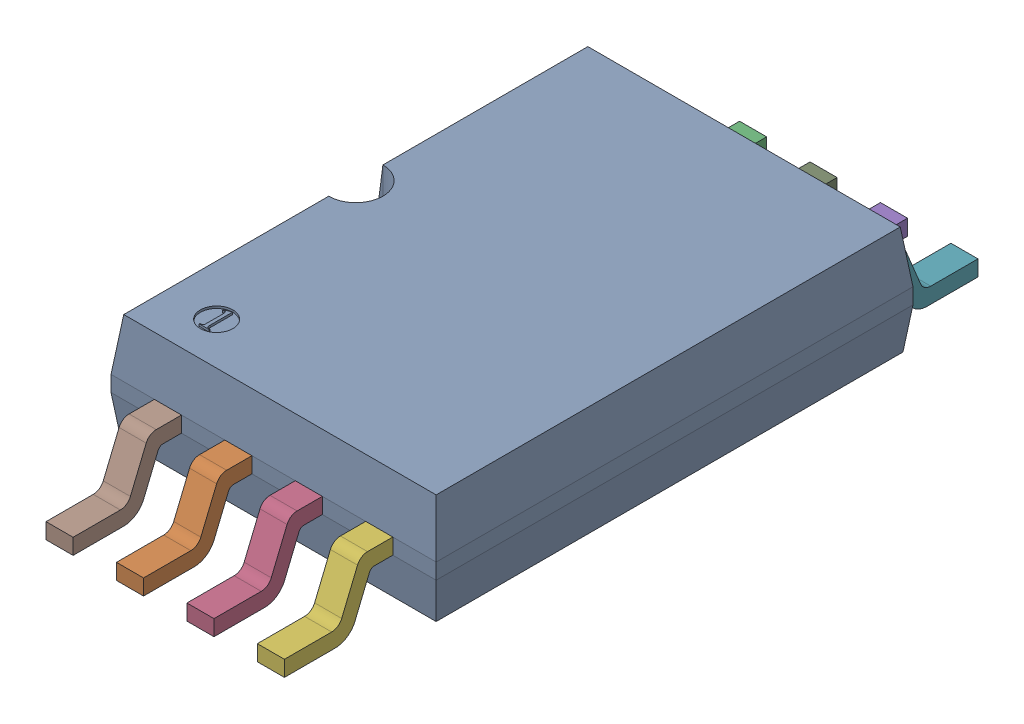
SolidWorks assembly tssop8_model.step, configuration Default. Lengths in mm.
Overall size (3 1.1 6.4).
9 component instances, 2 part files, 0 mates.
Components (placement in the parent):
- tssop8_body.step-1: tssop8_body.step [Default] at (-1.8727 -0.8115 1.5395) size (3 1 4.4)
- pin5to8_tssop8.step-1: pin5to8_tssop8.step [Default] at (-0.5727 -0.6665 1.5395) x (-1 0 0) z (0 0 -1) size (0.25 0.62 1.2)
- pin5to8_tssop8.step-2: pin5to8_tssop8.step [Default] at (-1.4727 -0.6665 -2.8605) size (0.25 0.62 1.2)
- pin5to8_tssop8.step-3: pin5to8_tssop8.step [Default] at (0.0773 -0.6665 1.5395) x (-1 0 0) z (0 0 -1) size (0.25 0.62 1.2)
- pin5to8_tssop8.step-4: pin5to8_tssop8.step [Default] at (-0.1727 -0.6665 -2.8605) size (0.25 0.62 1.2)
- pin5to8_tssop8.step-5: pin5to8_tssop8.step [Default] at (0.7273 -0.6665 1.5395) x (-1 0 0) z (0 0 -1) size (0.25 0.62 1.2)
- pin5to8_tssop8.step-6: pin5to8_tssop8.step [Default] at (0.4773 -0.6665 -2.8605) size (0.25 0.62 1.2)
- pin5to8_tssop8.step-7: pin5to8_tssop8.step [Default] at (-1.2227 -0.6665 1.5395) x (-1 0 0) z (0 0 -1) size (0.25 0.62 1.2)
- pin5to8_tssop8.step-8: pin5to8_tssop8.step [Default] at (-0.8227 -0.6665 -2.8605) size (0.25 0.62 1.2)
